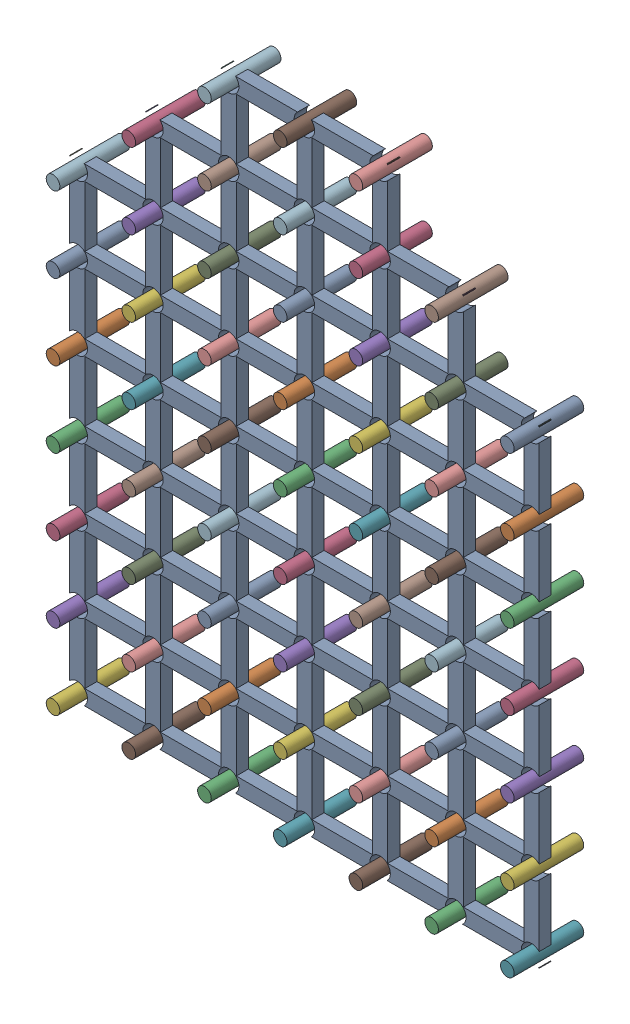
SolidWorks assembly 装配体1, configuration 默认. Lengths in mm.
Overall size (15.5 20.5 2.3).
2 component instances, 2 part files, 4 mates.
Components (placement in the parent):
- ConMarker-1: ConMarker [默认] at (-7.6559 -7.9983 -0.2) size (15.5 20.5 0.4)
- 零件1-1: 零件1 [默认] at (-7.9059 -7.7483 -1.3) size (15.45 20.45 2.3)
Mates (geometry in assembly coordinates):
- 宽度3: width: plane of ConMarker-1 through (-7.6559 7.5017 -0.2) normal (1 0 0); plane of ConMarker-1 through (7.3441 -7.4983 0.2) normal (0 1 0); cylinder of 零件1-1 through (-7.9059 -7.7483 1) axis (0 0 -1) radius 0.225
- 宽度4: width: plane of ConMarker-1 through (6.8441 2.9868 -0.2) normal (-1 0 0); plane of ConMarker-1 through (7.3441 -7.4983 0.2) normal (0 1 0); cylinder of 零件1-1 through (7.0941 -7.7483 1) axis (0 0 -1) radius 0.225
- 宽度5: width: plane of ConMarker-1 through (-0.1559 7.5017 -2.7495) normal (1 0 0); plane of ConMarker-1 through (-0.6559 7.5017 -2.7495) normal (-1 0 0); cylinder of 零件1-1 through (-0.4059 12.2517 1) axis (0 0 -1) radius 0.225
- 距离1: distance = 0.8 mm aligned: plane of ConMarker-1 through (-7.6559 -7.9983 0.2) normal (0 0 1); plane of 零件1-1 through (-5.4059 9.7517 1) normal (0 0 1)
